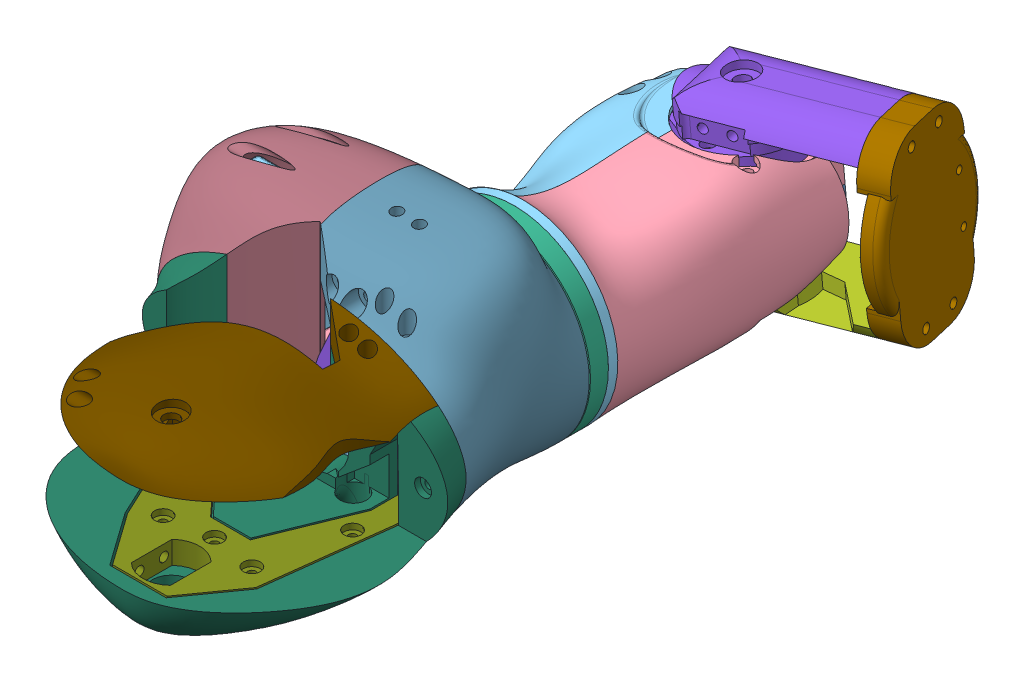
SolidWorks assembly arm new assm, configuration Default. Lengths in mm.
Overall size (221.09 125.75 380.28).
75 component instances, 28 part files, 41 mates.
Components (placement in the parent):
- gearbox-1: gearbox [Default] at (-106.8373 34.3024 -69.3555) x (-0.001457 0.999999 0) z (0.999999 0.001457 0) size (88.25 74 125.51)
  - bottom housing-1: bottom housing [Default] at (7.4002 -24.2748 89.7718) x (1 0 0) z (0 1 0) size (87.5 78 20)
  - wormscrew-1: wormscrew [Default] at (21.4002 -4.2748 74.7718) x (-0.98645 0.164063 0) z (0 0 1) size (40 40 51)
  - driveshaft cog-1: driveshaft cog [Default] at (-6.5998 -9.2748 103.2718) x (-0.999334 0 0.036493) z (0 1 0) size (49.29 49.31 47)
  - top housing-1: top housing [Default] at (-6.5998 15.7252 103.2718) x (-1 0 0) z (0 -1 0) size (87.5 78 40)
  - HS-805BB-1: HS-805BB [Default] at (2.9002 10.7252 28.6693) x (1 0 0) z (0 -1 0) size (83 68.8 30)
  - 608ZZ-4: 608ZZ [Default] at (21.4002 -4.2748 120.5718) x (0.996867 0.079098 0) z (0 0 1) size (22 22 7)
  - 6806 30x42x7-1: 6806 30x42x7 [Default] at (-6.5998 -15.2748 103.2718) x (0.979879 0 0.199591) z (0 -1 0) size (42 42 7)
  - 6806 30x42x7-2: 6806 30x42x7 [Default] at (-6.5998 2.7252 103.2718) x (0.968275 0 0.249889) z (0 1 0) size (42 42 7)
  - pot holder-1: pot holder [Default] at (-6.5998 15.7252 103.2718) x (0 0 -1) z (0 1 0) size (50 60 10)
  - cog brace-1: cog brace [Default] at (18.6002 10.0252 104.6718) x (-1 0 0) z (0 -1 0) size (8.5 22.65 3)
  - pot cog-1: pot cog [Default] at (18.6002 10.0252 97.7718) x (0.754384 0 -0.656434) z (0 1 0) size (28 27.88 7.9)
  - driveshaft-1: driveshaft [Default] at (-6.5998 -9.2748 103.2718) x (0.999334 0 -0.036493) z (0 -1 0) size (36.44 35.48 27)
  - Pan Head Cross Recess Screw_ISO-22: Pan Head Cross Recess Screw_ISO [ISO 7045 - M3 x 10 - Z --- 10N] at (-26.5998 23.1252 103.2718) x (0 -1 0) z (0 0 1) size (12.35 5.6 5.6)
  - Pan Head Cross Recess Screw_ISO-23: Pan Head Cross Recess Screw_ISO [ISO 7045 - M3 x 10 - Z --- 10N] at (-6.5998 23.1252 123.2718) x (0 -1 0) z (0.495758 0 0.868461) size (12.35 5.6 5.6)
  - Pan Head Cross Recess Screw_ISO-24: Pan Head Cross Recess Screw_ISO [ISO 7045 - M3 x 10 - Z --- 10N] at (-6.5998 23.1252 83.2718) x (0 -1 0) z (0.927545 0 0.373711) size (12.35 5.6 5.6)
  - Pan Head Cross Recess Screw_ISO-3: Pan Head Cross Recess Screw_ISO [ISO 7045 - M5 x 12 - Z --- 12N] at (-34.5998 -13.2748 42.0718) x (0 0 1) z (-1 0 0) size (15.63 9.5 9.5)
  - Pan Head Cross Recess Screw_ISO-4: Pan Head Cross Recess Screw_ISO [ISO 7045 - M5 x 12 - Z --- 12N] at (-34.5998 4.7252 42.0718) x (0 0 1) z (-1 0 0) size (15.63 9.5 9.5)
  - Pan Head Cross Recess Screw_ISO-9: Pan Head Cross Recess Screw_ISO [ISO 7045 - M3 x 30 - Z --- 25N] at (36.9002 14.1252 123.7718) x (0 -1 0) z (0 0 1) size (32.35 5.6 5.6)
  - Pan Head Cross Recess Screw_ISO-13: Pan Head Cross Recess Screw_ISO [ISO 7045 - M3 x 30 - Z --- 25N] at (-18.0998 -22.6748 69.7718) x (0 1 0) z (0 0 1) size (32.35 5.6 5.6)
  - Pan Head Cross Recess Screw_ISO-14: Pan Head Cross Recess Screw_ISO [ISO 7045 - M3 x 30 - Z --- 25N] at (34.9002 14.1252 82.7718) x (0 -1 0) z (-0.981395 0 -0.191999) size (32.35 5.6 5.6)
  - Pan Head Cross Recess Screw_ISO-15: Pan Head Cross Recess Screw_ISO [ISO 7045 - M3 x 30 - Z --- 25N] at (-5.5998 14.1252 71.7718) x (0 -1 0) z (0.38373 0 0.923445) size (32.35 5.6 5.6)
  - Pan Head Cross Recess Screw_ISO-16: Pan Head Cross Recess Screw_ISO [ISO 7045 - M2 x 6 - Z --- 6N] at (18.6002 6.9252 115.2718) x (0 1 0) z (0.879308 0 -0.476254) size (7.57 4 4)
  - Pan Head Cross Recess Screw_ISO-18: Pan Head Cross Recess Screw_ISO [ISO 7045 - M3 x 5 - Z --- 5N] at (-5.9795 -13.6748 120.2605) x (0 1 0) z (-0.276322 0 0.961065) size (7.35 5.6 5.6)
  - Pan Head Cross Recess Screw_ISO-19: Pan Head Cross Recess Screw_ISO [ISO 7045 - M3 x 5 - Z --- 5N] at (7.8026 -13.6748 94.2402) x (0 1 0) z (0 0 1) size (7.35 5.6 5.6)
  - Pan Head Cross Recess Screw_ISO-20: Pan Head Cross Recess Screw_ISO [ISO 7045 - M3 x 5 - Z --- 5N] at (-21.6227 -13.6748 95.3147) x (0 1 0) z (-0.051559 0 0.99867) size (7.35 5.6 5.6)
  - Pan Head Cross Recess Screw_ISO-21: Pan Head Cross Recess Screw_ISO [ISO 7045 - M3 x 30 - Z --- 25N] at (-27.0895 14.1252 123.7718) x (0 -1 0) z (-0.304842 0 0.952403) size (32.35 5.6 5.6)
  - Pan Head Cross Recess Screw_ISO-2: Pan Head Cross Recess Screw_ISO [ISO 7045 - M5 x 12 - Z --- 12N] at (40.4002 4.7252 42.0718) x (0 0 1) z (0.747712 -0.664023 0) size (15.63 9.5 9.5)
  - Pan Head Cross Recess Screw_ISO-1: Pan Head Cross Recess Screw_ISO [ISO 7045 - M5 x 12 - Z --- 12N] at (40.4002 -13.2748 42.0718) x (0 0 1) z (0.337086 -0.941474 0) size (15.63 9.5 9.5)
- arm middle back-1: arm middle back [Default] at (-33.5596 9.8746 -51.8062) x (0 0 1) z (-1 0 0) size (90.34 121.18 102.39)
- arm middle front-1: arm middle front [Default] at (-3.5596 36.8746 -34.4409) x (-1 0 0) z (0 0 -1) size (140.79 123.83 87.16)
- arm top left-1: arm top left [Default] at (-11.0685 4.8746 -34.4409) size (182.35 104.85 120.87)
- top brace-1: top brace [Default] at (-3.5596 4.8746 57.5591) x (1 0 0) z (0 -1 0) size (182.35 135.45 104.85)
- left glue widget-1: left glue widget [Default] at (-24.8829 -16.5899 -28.5953) x (0 0 1) z (0 1 0) size (13 9 6)
- arm top right-1: arm top right [Default] at (-3.5596 55.8746 57.5591) x (0 0 -1) z (0 1 0) size (132 144.11 34.63)
- gearbox screw block 2-1: gearbox screw block 2 [Default] at (-8.7634 83.7455 -72.2507) x (0.999999 0.001457 0) z (0.001457 -0.999999 0) size (26 29.8 14.3)
- gearbox screw block 1-1: gearbox screw block 1 [Default] at (-26.9977 -12.1811 -72.2155) x (0.999999 0.001457 0) z (-0.001457 0.999999 0) size (10 29.5 20)
- arm rot mount-1: arm rot mount [Default] at (-3.556 27.8531 -124.6303) x (-0.996744 -0.080636 0) z (0 0 1) size (66 66 31)
- lower arm assm-1: lower arm assm [Default] at (-84.5469 4.371 -95.9679) x (-0.995302 -0.096816 0) z (0 0 -1) size (111.83 109.64 138.38)
  - arm lower bottom-1: arm lower bottom [Default] at (-82.8839 14.8285 33.6624) size (61.83 109.64 120.63)
  - arm lower top-1: arm lower top [Default] at (-82.8839 14.8285 33.6624) size (102.83 109.64 125.02)
  - gearbox-1: gearbox [Default] at (-90.004 25.8046 38.1582) size (88.25 74 125.51)
    - bottom housing-1: bottom housing [Default] at (7.4002 -24.2748 89.7718) x (1 0 0) z (0 1 0) size (87.5 78 20)
    - wormscrew-1: wormscrew [Default] at (21.4002 -4.2748 74.7718) x (-0.98645 0.164063 0) z (0 0 1) size (40 40 51)
    - driveshaft cog-1: driveshaft cog [Default] at (-6.5998 -9.2748 103.2718) x (-0.999334 0 0.036493) z (0 1 0) size (49.29 49.31 47)
    - top housing-1: top housing [Default] at (-6.5998 15.7252 103.2718) x (-1 0 0) z (0 -1 0) size (87.5 78 40)
    - HS-805BB-1: HS-805BB [Default] at (2.9002 10.7252 28.6693) x (1 0 0) z (0 -1 0) size (83 68.8 30)
    - 608ZZ-4: 608ZZ [Default] at (21.4002 -4.2748 120.5718) x (0.996867 0.079098 0) z (0 0 1) size (22 22 7)
    - 6806 30x42x7-1: 6806 30x42x7 [Default] at (-6.5998 -15.2748 103.2718) x (0.979879 0 0.199591) z (0 -1 0) size (42 42 7)
    - 6806 30x42x7-2: 6806 30x42x7 [Default] at (-6.5998 2.7252 103.2718) x (0.968275 0 0.249889) z (0 1 0) size (42 42 7)
    - pot holder-1: pot holder [Default] at (-6.5998 15.7252 103.2718) x (0 0 -1) z (0 1 0) size (50 60 10)
    - cog brace-1: cog brace [Default] at (18.6002 10.0252 104.6718) x (-1 0 0) z (0 -1 0) size (8.5 22.65 3)
    - pot cog-1: pot cog [Default] at (18.6002 10.0252 97.7718) x (0.754384 0 -0.656434) z (0 1 0) size (28 27.88 7.9)
    - driveshaft-1: driveshaft [Default] at (-6.5998 -9.2748 103.2718) x (0.999334 0 -0.036493) z (0 -1 0) size (36.44 35.48 27)
    - Pan Head Cross Recess Screw_ISO-22: Pan Head Cross Recess Screw_ISO [ISO 7045 - M3 x 10 - Z --- 10N] at (-26.5998 23.1252 103.2718) x (0 -1 0) z (0 0 1) size (12.35 5.6 5.6)
    - Pan Head Cross Recess Screw_ISO-23: Pan Head Cross Recess Screw_ISO [ISO 7045 - M3 x 10 - Z --- 10N] at (-6.5998 23.1252 123.2718) x (0 -1 0) z (0.495758 0 0.868461) size (12.35 5.6 5.6)
    - Pan Head Cross Recess Screw_ISO-24: Pan Head Cross Recess Screw_ISO [ISO 7045 - M3 x 10 - Z --- 10N] at (-6.5998 23.1252 83.2718) x (0 -1 0) z (0.927545 0 0.373711) size (12.35 5.6 5.6)
    - Pan Head Cross Recess Screw_ISO-3: Pan Head Cross Recess Screw_ISO [ISO 7045 - M5 x 12 - Z --- 12N] at (-34.5998 -13.2748 42.0718) x (0 0 1) z (-1 0 0) size (15.63 9.5 9.5)
    - Pan Head Cross Recess Screw_ISO-4: Pan Head Cross Recess Screw_ISO [ISO 7045 - M5 x 12 - Z --- 12N] at (-34.5998 4.7252 42.0718) x (0 0 1) z (-1 0 0) size (15.63 9.5 9.5)
    - Pan Head Cross Recess Screw_ISO-9: Pan Head Cross Recess Screw_ISO [ISO 7045 - M3 x 30 - Z --- 25N] at (36.9002 14.1252 123.7718) x (0 -1 0) z (0 0 1) size (32.35 5.6 5.6)
    - Pan Head Cross Recess Screw_ISO-13: Pan Head Cross Recess Screw_ISO [ISO 7045 - M3 x 30 - Z --- 25N] at (-18.0998 -22.6748 69.7718) x (0 1 0) z (0 0 1) size (32.35 5.6 5.6)
    - Pan Head Cross Recess Screw_ISO-14: Pan Head Cross Recess Screw_ISO [ISO 7045 - M3 x 30 - Z --- 25N] at (34.9002 14.1252 82.7718) x (0 -1 0) z (-0.981395 0 -0.191999) size (32.35 5.6 5.6)
    - Pan Head Cross Recess Screw_ISO-15: Pan Head Cross Recess Screw_ISO [ISO 7045 - M3 x 30 - Z --- 25N] at (-5.5998 14.1252 71.7718) x (0 -1 0) z (0.38373 0 0.923445) size (32.35 5.6 5.6)
    - Pan Head Cross Recess Screw_ISO-16: Pan Head Cross Recess Screw_ISO [ISO 7045 - M2 x 6 - Z --- 6N] at (18.6002 6.9252 115.2718) x (0 1 0) z (0.879308 0 -0.476254) size (7.57 4 4)
    - Pan Head Cross Recess Screw_ISO-18: Pan Head Cross Recess Screw_ISO [ISO 7045 - M3 x 5 - Z --- 5N] at (-5.9795 -13.6748 120.2605) x (0 1 0) z (-0.276322 0 0.961065) size (7.35 5.6 5.6)
    - Pan Head Cross Recess Screw_ISO-19: Pan Head Cross Recess Screw_ISO [ISO 7045 - M3 x 5 - Z --- 5N] at (7.8026 -13.6748 94.2402) x (0 1 0) z (0 0 1) size (7.35 5.6 5.6)
    - Pan Head Cross Recess Screw_ISO-20: Pan Head Cross Recess Screw_ISO [ISO 7045 - M3 x 5 - Z --- 5N] at (-21.6227 -13.6748 95.3147) x (0 1 0) z (-0.051559 0 0.99867) size (7.35 5.6 5.6)
    - Pan Head Cross Recess Screw_ISO-21: Pan Head Cross Recess Screw_ISO [ISO 7045 - M3 x 30 - Z --- 25N] at (-27.0895 14.1252 123.7718) x (0 -1 0) z (-0.304842 0 0.952403) size (32.35 5.6 5.6)
    - Pan Head Cross Recess Screw_ISO-2: Pan Head Cross Recess Screw_ISO [ISO 7045 - M5 x 12 - Z --- 12N] at (40.4002 4.7252 42.0718) x (0 0 1) z (0.747712 -0.664023 0) size (15.63 9.5 9.5)
    - Pan Head Cross Recess Screw_ISO-1: Pan Head Cross Recess Screw_ISO [ISO 7045 - M5 x 12 - Z --- 12N] at (40.4002 -13.2748 42.0718) x (0 0 1) z (0.337086 -0.941474 0) size (15.63 9.5 9.5)
- ring cover-1: ring cover [Default] at (-3.556 27.8531 -124.6303) x (0.096816 -0.995302 0) z (0 0 1) size (100 100 9.5)
- elbow left-1: elbow left [Default] at (13.6334 -7.1478 -237.3978) x (-0.964855 -0.093854 0.245453) z (-0.096816 0.995302 0) size (91.97 52.06 22)
- elbow right-1: elbow right [Default] at (4.4359 87.4059 -237.3978) x (0.964855 0.093854 -0.245453) z (0.096816 -0.995302 0) size (91.97 52.06 22)
- elbow bottom-1: elbow bottom [Default] at (86.1838 47.6336 -257.1895) x (-0.096816 0.995302 0) z (-0.964855 -0.093854 0.245453) size (95 77.15 15.7)
- ELBOW BRACE-1: ELBOW BRACE [Default] at (56.1264 34.3829 -275.1153) x (0.096816 -0.995302 0) z (0.2443 0.023764 0.969409) size (71 35 8)
Mates (geometry in assembly coordinates):
- Concentric2: concentric anti-aligned: cylinder of gearbox-1/driveshaft-1; cylinder of arm middle front-1
- Coincident1: coincident anti-aligned: plane of gearbox-1/top housing-1 through (-39.0632 32.8013 -53.6303) normal (0 0 1); plane of arm middle front-1 through (22.4404 64.6526 -53.6303) normal (0 0 -1)
- Concentric5: concentric aligned: circle of gearbox-1/top housing-1; circle of arm middle front-1
- Coincident10: coincident anti-aligned: plane of arm middle back-1 through (-33.5596 36.8746 125.5591) normal (1 0 0); plane of arm middle front-1 through (-33.5596 36.8746 125.5591) normal (-1 0 0)
- Coincident11: coincident aligned: plane of arm middle back-1 through (-3.5596 36.8746 -114.4409) normal (0 0 -1); plane of arm middle front-1 through (-3.5596 36.8746 -114.4409) normal (0 0 -1)
- Coincident12: coincident anti-aligned: plane of arm middle back-1 through (-3.5596 36.8746 -34.4409) normal (0 0 1); plane of arm top left-1 through (-3.5596 36.8746 -34.4409) normal (0 0 -1)
- Coincident13: coincident anti-aligned: plane of arm top left-1 through (39.6862 -1.1254 -55.2808) normal (0 1 0); plane of top brace-1 through (25.613 -1.1254 -49.893) normal (0 -1 0)
- Parallel3: parallel anti-aligned: line of arm middle front-1; line of arm top left-1
- Coincident18: coincident anti-aligned: plane of arm top left-1 through (-15.5596 -10.5899 -30.4409) normal (0 0 -1); plane of left glue widget-1 through (-16.0596 -10.5899 -30.4409) normal (0 0 1)
- Coincident19: coincident anti-aligned: plane of arm top left-1 through (-15.5596 -16.5899 -30.4409) normal (0 1 0); plane of left glue widget-1 through (-25.0596 -16.5899 -43.4409) normal (0 -1 0)
- Distance2: distance = 0.5 mm anti-aligned: plane of left glue widget-1 through (-25.0596 -10.5899 -43.4409) normal (-1 0 0); plane of arm top left-1 through (-25.5596 -16.5899 -30.4409) normal (1 0 0)
- Coincident22: coincident anti-aligned: plane of arm middle front-1 through (-3.5596 36.8746 -34.4409) normal (0 0 1); plane of arm top right-1 through (-3.5596 36.8746 -34.4409) normal (0 0 -1)
- Coincident23: coincident anti-aligned: plane of arm top left-1 through (-3.5596 55.8746 125.5591) normal (0 1 0); plane of arm top right-1 through (72.9205 55.8746 96.2294) normal (0 -1 0)
- Coincident24: coincident: point of arm top left-1; point of arm top right-1
- Parallel4: parallel anti-aligned: line of arm top left-1; line of top brace-1
- Concentric10: concentric aligned: cylinder of arm top left-1; cylinder of top brace-1
- Coincident26: coincident: point of arm middle back-1; point of arm middle front-1
- Coincident27: coincident anti-aligned: plane of arm middle back-1 through (-3.5596 36.8746 -34.4409) normal (0 0 1); plane of arm top left-1 through (-3.5596 36.8746 -34.4409) normal (0 0 -1)
- Coincident28: coincident: point of arm middle back-1; point of arm top left-1
- Coincident30: coincident anti-aligned: plane of gearbox-1/top housing-1 through (-25.1143 67.8596 -58.6303) normal (0 0 -1); plane of gearbox screw block 2-1 through (-21.8878 69.4264 -58.6303) normal (0 0 1)
- Concentric12: concentric anti-aligned: circle of gearbox-1/top housing-1; cylinder of gearbox screw block 2-1
- Concentric13: concentric anti-aligned: circle of gearbox-1/top housing-1; circle of gearbox screw block 2-1
- Concentric14: concentric aligned: circle of gearbox-1/top housing-1; cylinder of gearbox screw block 1-1
- Coincident31: coincident anti-aligned: plane of gearbox-1/top housing-1 through (-32.3895 19.5689 -58.6303) normal (0 0 -1); plane of gearbox screw block 1-1 through (-31.7048 7.812 -58.6303) normal (0 0 1)
- Parallel5: parallel anti-aligned: plane of gearbox-1/top housing-1 through (-33.0484 22.639 -73.6303) normal (0.999999 0.001457 0); plane of gearbox screw block 1-1 through (-31.7048 7.812 -88.1303) normal (-0.999999 -0.001457 0)
- Concentric15: concentric aligned: cylinder of arm middle front-1; cylinder of arm rot mount-1
- Coincident32: coincident anti-aligned: plane of gearbox-1/bottom housing-1 through (21.9841 0.3903 -93.6303) normal (0 0 -1); plane of arm rot mount-1 through (-3.556 27.8531 -93.6303) normal (0 0 1)
- Coincident33: coincident anti-aligned: circle of arm rot mount-1; circle of ?
- Coincident34: coincident anti-aligned: circle of arm rot mount-1; circle of ?
- Coincident35: coincident anti-aligned: plane of ? through (-3.556 27.8531 -124.6303) normal (0 0 1); plane of ring cover-1 through (-3.556 27.8531 -124.6303) normal (0 0 -1)
- Coincident36: coincident aligned: circle of ?; circle of ring cover-1
- Coincident39: coincident aligned: circle of ?; circle of ring cover-1
- Coincident41: coincident anti-aligned: circle of elbow left-1; circle of elbow bottom-1
- Coincident42: coincident anti-aligned: circle of elbow left-1; circle of elbow bottom-1
- Coincident43: coincident anti-aligned: circle of elbow right-1; circle of elbow bottom-1
- Coincident44: coincident anti-aligned: circle of elbow right-1; circle of elbow bottom-1
- Concentric16: concentric anti-aligned: circle of elbow left-1; cylinder of lower arm assm-1/gearbox-1/driveshaft-1
- Coincident45: coincident anti-aligned: plane of lower arm assm-1/gearbox-1/driveshaft cog-1 through (-3.9773 64.4837 -222.026) normal (-0.096816 0.995302 0); plane of elbow right-1 through (-15.8166 63.3321 -203.9908) normal (0.096816 -0.995302 0)
- Coincident47: coincident anti-aligned: plane of elbow left-1 through (12.4716 4.7958 -237.3978) normal (-0.096816 0.995302 0); plane of ELBOW BRACE-1 through (70.9863 10.4877 -270.0219) normal (0.096816 -0.995302 0)
- Coincident48: coincident: line of elbow left-1; plane of ELBOW BRACE-1 through (33.2123 78.1485 -270.4136) normal (-0.2443 -0.023764 -0.969409)
- Coincident49: coincident anti-aligned: plane of ELBOW BRACE-1; plane of ELBOW BRACE-1
